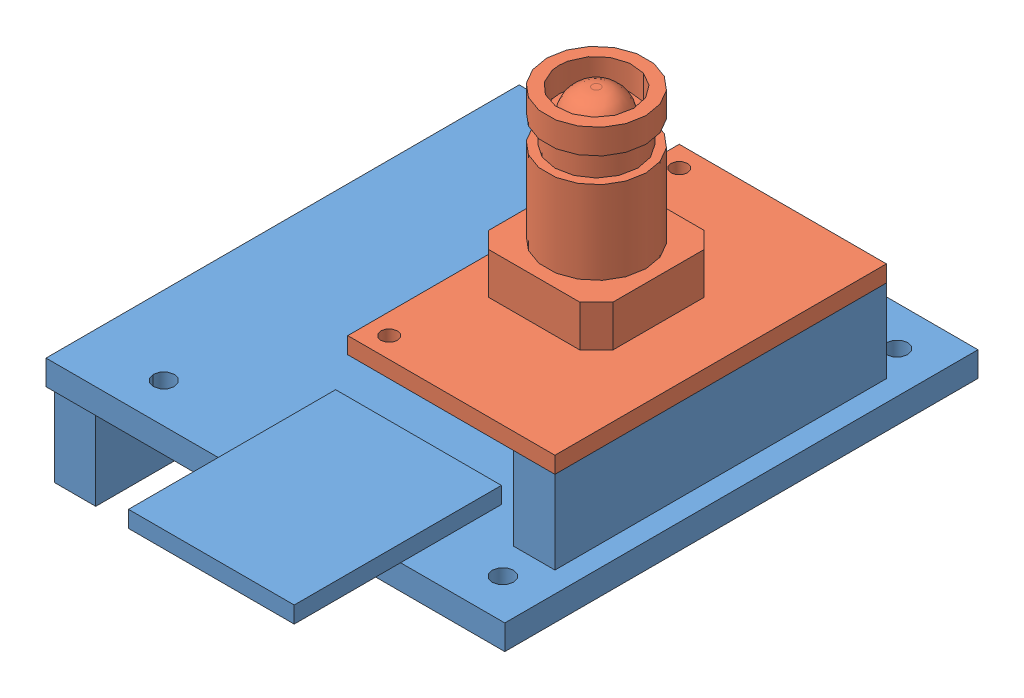
SolidWorks assembly Assemblage1, configuration Default. Lengths in mm.
Overall size (55.36 46 72.76).
2 component instances, 2 part files, 3 mates.
Components (placement in the parent):
- Support_carte_CMUCam-1: Support_carte_CMUCam [Default] at (-32.4227 6.6898 20.4899) size (55.36 23 72.76)
- Optique_Cmucam-1: Optique_Cmucam [Default] at (-4.5627 19.6898 -28.0601) x (0 0 1) z (-1 0 0) size (40 23 25)
Mates (geometry in assembly coordinates):
- Coïncidente1: coincident: plane of Support_carte_CMUCam-1 through (15.4373 19.6898 11.9399) normal (0 1 0); plane of ? through (20.4373 19.6898 -25.6558) normal (0 -1 0)
- Coïncidente2: coincident: plane of ? through (20.4373 21.6898 -25.6558) normal (1 0 0); plane of Support_carte_CMUCam-1 through (20.4373 19.6898 -28.0601) normal (1 0 0)
- Coïncidente3: coincident aligned: plane of Support_carte_CMUCam-1 through (15.4373 19.6898 -28.0601) normal (0 0 -1); plane of ? through (-4.5627 21.6898 -25.6558) normal (0 0 -1)
